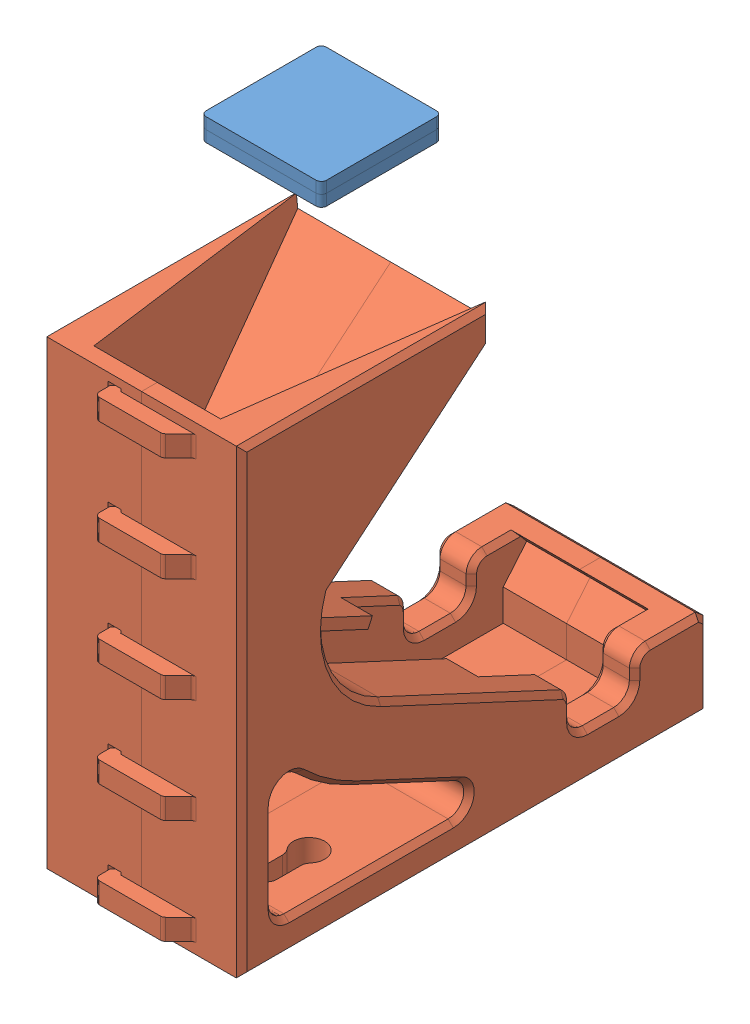
SolidWorks assembly flipper_v2, configuration Default. Lengths in mm.
Overall size (38.2 116.27 95.2).
2 component instances, 2 part files, 6 mates.
Components (placement in the parent):
- tile-1: tile [Default] at (18.5836 116.2733 -34.8592) x (-1 0 0) z (0 0 1) size (23 4.3 23)
- slide_1 (2)-1: slide_1 (2) [Default] at (31.2 70 -31.3209) x (0 0 1) z (-1 0 0) size (95.2 88 38.2)
Mates (geometry in assembly coordinates):
- Coincident1: coincident anti-aligned: plane of slide_1 (2)-1 through (0 70 -31.3209) normal (-1 0 0)
- Coincident2: coincident anti-aligned: plane of slide_1 (2)-1 through (19.1 0 -54) normal (0 -1 0)
- Coincident3: coincident aligned: plane of slide_1 (2)-1 through (19.1 70 0) normal (0 0 1)
- Parallel1: parallel: plane of tile-1 through (29.0836 111.9733 -24.3592) normal (0 -1 0); plane of slide_1 (2)-1 through (19.1 88 -3) normal (0 1 0)
- Parallel2: parallel aligned: plane of tile-1 through (30.0836 111.9733 -24.3592) normal (1 0 0); plane of slide_1 (2)-1 through (0 70 -31.3209) normal (-1 0 0)
- Parallel3: parallel: plane of tile-1 through (29.0836 116.2733 -24.3592) normal (0 1 0); plane of slide_1 (2)-1 through (19.1 88 -3) normal (0 1 0)
